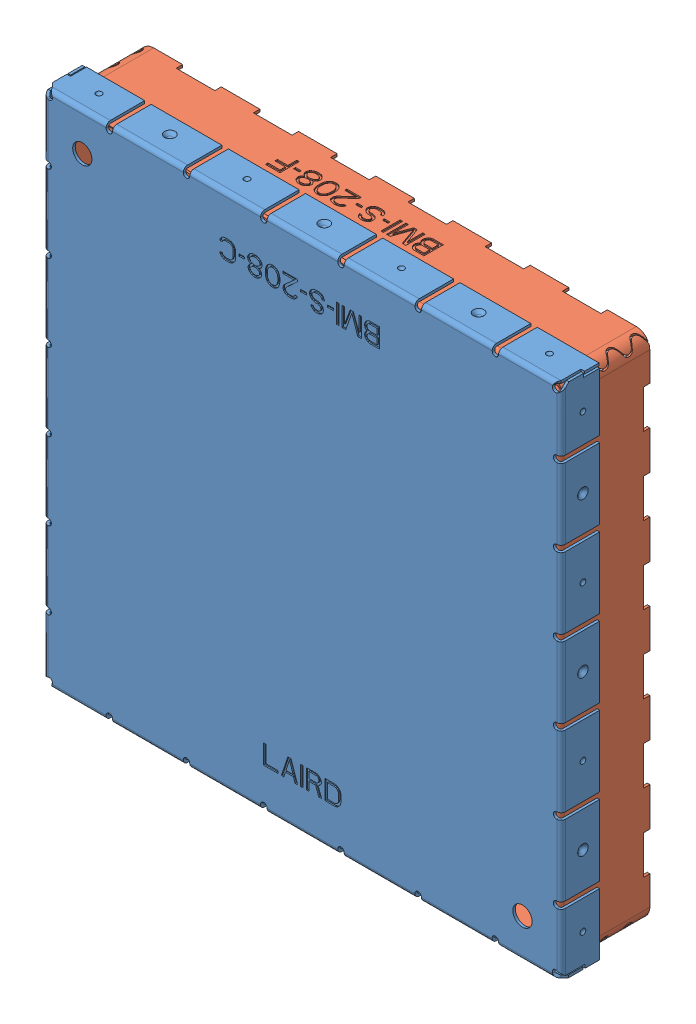
SolidWorks assembly S1PCB, configuration Default. Lengths in mm.
Overall size (41.61 42.42 8.64).
3 component instances, 2 part files, 0 mates.
Components (placement in the parent):
- Laird-BMI-S-208-F__AND__BMI-S-208-C-1: Laird-BMI-S-208-F__AND__BMI-S-208-C [Default] at (138.6 103.5002 7.0128) x (-1 0 0) z (0 1 0) size (41.61 8.64 42.42)
  - Laird-DEFAULT_Laird-BMI-S-208-F__and__BMI-S-208-C_BMI-S-208-C-1: Laird-DEFAULT_Laird-BMI-S-208-F__and__BMI-S-208-C_BMI-S-208-C [Default] at (0 20 0) size (40.2 3 40.2)
  - Laird-DEFAULT_Laird-BMI-S-208-F__and__BMI-S-208-C_BMI-S-208-F-1: Laird-DEFAULT_Laird-BMI-S-208-F__and__BMI-S-208-C_BMI-S-208-F [Default] at (0 19.8 0) size (41.61 8.64 42.42)
